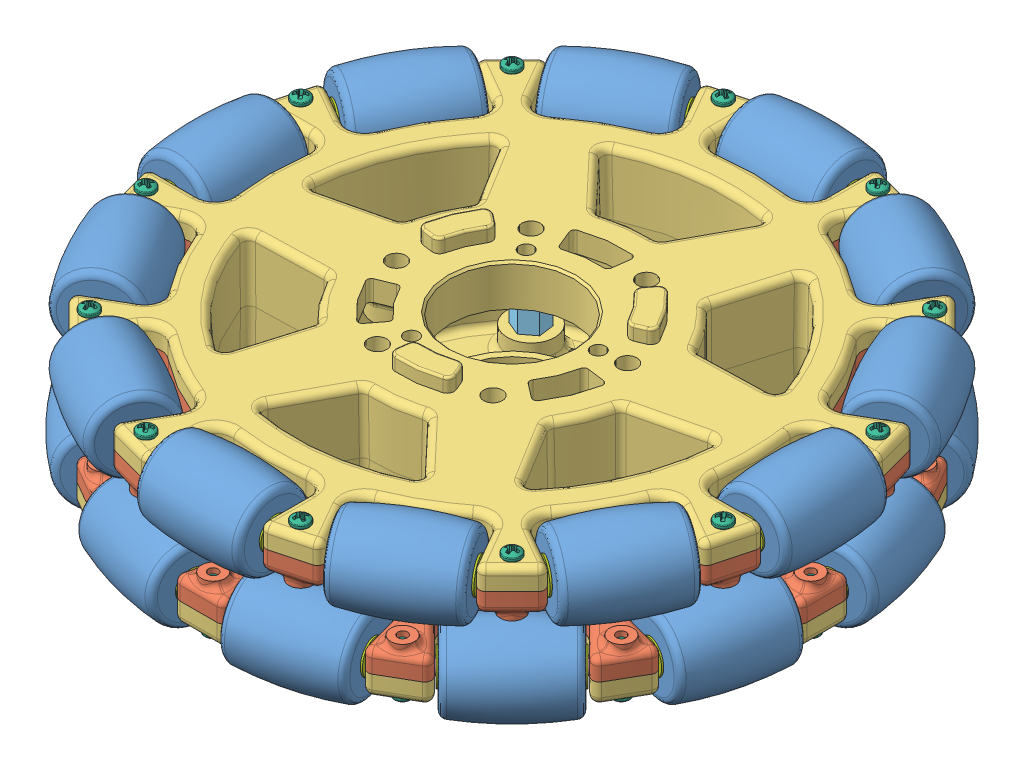
SolidWorks assembly 217-2585.20121203, configuration Default. Lengths in mm.
Overall size (174.23 42.44 174.23).
129 component instances, 7 part files, 0 mates.
Components (placement in the parent):
- 217-2585-001 Rev1-1: 217-2585-001 Rev1 [Default] at (0 9.4629 -66.8297) x (1 0 0) z (0 -0.857126 0.515108) size (24.13 18.81 18.81)
- 217-2585-002 Rev1-1: 217-2585-002 Rev1 [Default] x (1 0 0) z (0 1 0) size (145.16 145.16 19.05)
- 217-2585-001 Rev1-2: 217-2585-001 Rev1 [Default] at (47.2557 -9.4629 47.2557) x (-0.707107 0 0.707107) z (-0.700403 -0.137373 -0.700403) size (24.13 18.81 18.81)
- 217-2585-001 Rev1-3: 217-2585-001 Rev1 [Default] at (17.2968 -9.4629 64.5525) x (-0.965926 0 0.258819) z (-0.256365 -0.137373 -0.956768) size (24.13 18.81 18.81)
- 217-2585-001 Rev1-4: 217-2585-001 Rev1 [Default] at (-17.2968 -9.4629 64.5525) x (-0.965926 0 -0.258819) z (0.256365 -0.137373 -0.956768) size (24.13 18.81 18.81)
- 217-2585-001 Rev1-5: 217-2585-001 Rev1 [Default] at (-47.2557 -9.4629 47.2557) x (-0.707107 0 -0.707107) z (0.700403 -0.137373 -0.700403) size (24.13 18.81 18.81)
- 217-2585-001 Rev1-6: 217-2585-001 Rev1 [Default] at (-64.5525 -9.4629 17.2968) x (-0.258819 0 -0.965926) z (0.956768 -0.137373 -0.256365) size (24.13 18.81 18.81)
- 217-2585-001 Rev1-7: 217-2585-001 Rev1 [Default] at (-64.5525 -9.4629 -17.2968) x (0.258819 0 -0.965926) z (0.956768 -0.137373 0.256365) size (24.13 18.81 18.81)
- 217-2585-001 Rev1-8: 217-2585-001 Rev1 [Default] at (-47.2557 -9.4629 -47.2557) x (0.707107 0 -0.707107) z (0.700403 -0.137373 0.700403) size (24.13 18.81 18.81)
- 217-2585-001 Rev1-9: 217-2585-001 Rev1 [Default] at (-17.2968 -9.4629 -64.5525) x (0.965926 0 -0.258819) z (0.256365 -0.137373 0.956768) size (24.13 18.81 18.81)
- 217-2585-001 Rev1-10: 217-2585-001 Rev1 [Default] at (17.2968 -9.4629 -64.5525) x (0.965926 0 0.258819) z (-0.256365 -0.137373 0.956768) size (24.13 18.81 18.81)
- 217-2585-001 Rev1-11: 217-2585-001 Rev1 [Default] at (47.2557 -9.4629 -47.2557) x (0.707107 0 0.707107) z (-0.700403 -0.137373 0.700403) size (24.13 18.81 18.81)
- 217-2585-001 Rev1-12: 217-2585-001 Rev1 [Default] at (64.5525 -9.4629 -17.2968) x (0.258819 0 0.965926) z (-0.956768 -0.137373 0.256365) size (24.13 18.81 18.81)
- 217-2585-001 Rev1-13: 217-2585-001 Rev1 [Default] at (64.5525 -9.4629 17.2968) x (-0.258819 0 0.965926) z (-0.956768 -0.137373 -0.256365) size (24.13 18.81 18.81)
- 217-2585-003 Rev2-1: 217-2585-003 Rev2 [Default] at (0 -9.525 0) x (0.965926 0 -0.258819) z (0 -1 0) size (142.26 142.26 17.6)
- 217-2585-004 Rev1-1: 217-2585-004 Rev1 [Default] at (-57.9397 9.4629 -33.3049) x (0.5 0 -0.866025) z (-0.558431 0.764334 -0.32241) size (30.16 3 3)
- 217-2585-004 Rev1-2: 217-2585-004 Rev1 [Default] at (-64.5197 -9.4629 -17.4195) x (0.258819 0 -0.965926) z (-0.83871 -0.496046 -0.224732) size (30.16 3 3)
- 217-2585-003 Rev2-2: 217-2585-003 Rev2 [Default] at (0 9.525 0) x (-1 0 0) z (0 1 0) size (142.26 142.26 17.6)
- 217-2585-004 Rev1-3: 217-2585-004 Rev1 [Default] at (-33.5248 9.4629 -57.8127) x (0.866025 0 -0.5) z (-0.32241 0.764334 -0.558431) size (30.16 3 3)
- 217-2585-004 Rev1-4: 217-2585-004 Rev1 [Default] at (-0.127 9.4629 -66.8297) x (1 0 0) z (0 0.764334 -0.644821) size (30.16 3 3)
- 217-2585-004 Rev1-5: 217-2585-004 Rev1 [Default] at (33.3049 9.4629 -57.9397) x (0.866025 0 0.5) z (0.32241 0.764334 -0.558431) size (30.16 3 3)
- 217-2585-004 Rev1-6: 217-2585-004 Rev1 [Default] at (57.8127 9.4629 -33.5248) x (0.5 0 0.866025) z (0.558431 0.764334 -0.32241) size (30.16 3 3)
- 217-2585-004 Rev1-7: 217-2585-004 Rev1 [Default] at (66.8297 9.4629 -0.127) x (0 0 1) z (0.644821 0.764334 0) size (30.16 3 3)
- 217-2585-004 Rev1-8: 217-2585-004 Rev1 [Default] at (57.9397 9.4629 33.3049) x (-0.5 0 0.866025) z (0.558431 0.764334 0.32241) size (30.16 3 3)
- 217-2585-004 Rev1-9: 217-2585-004 Rev1 [Default] at (33.5248 9.4629 57.8127) x (-0.866025 0 0.5) z (0.32241 0.764334 0.558431) size (30.16 3 3)
- 217-2585-004 Rev1-10: 217-2585-004 Rev1 [Default] at (0.127 9.4629 66.8297) x (-1 0 0) z (0 0.764334 0.644821) size (30.16 3 3)
- 217-2585-004 Rev1-11: 217-2585-004 Rev1 [Default] at (-33.3049 9.4629 57.9397) x (-0.866025 0 -0.5) z (-0.32241 0.764334 0.558431) size (30.16 3 3)
- 217-2585-004 Rev1-12: 217-2585-004 Rev1 [Default] at (-57.8127 9.4629 33.5248) x (-0.5 0 -0.866025) z (-0.558431 0.764334 0.32241) size (30.16 3 3)
- 217-2585-004 Rev1-13: 217-2585-004 Rev1 [Default] at (-66.8297 9.4629 0.127) x (0 0 -1) z (-0.644821 0.764334 0) size (30.16 3 3)
- 217-2585-004 Rev1-14: 217-2585-004 Rev1 [Default] at (-47.1659 -9.4629 -47.3455) x (0.707107 0 -0.707107) z (-0.613978 -0.496046 -0.613978) size (30.16 3 3)
- 217-2585-004 Rev1-15: 217-2585-004 Rev1 [Default] at (-17.1741 -9.4629 -64.5854) x (0.965926 0 -0.258819) z (-0.224732 -0.496046 -0.83871) size (30.16 3 3)
- 217-2585-004 Rev1-16: 217-2585-004 Rev1 [Default] at (17.4195 -9.4629 -64.5197) x (0.965926 0 0.258819) z (0.224732 -0.496046 -0.83871) size (30.16 3 3)
- 217-2585-004 Rev1-17: 217-2585-004 Rev1 [Default] at (47.3455 -9.4629 -47.1659) x (0.707107 0 0.707107) z (0.613978 -0.496046 -0.613978) size (30.16 3 3)
- 217-2585-004 Rev1-18: 217-2585-004 Rev1 [Default] at (64.5854 -9.4629 -17.1741) x (0.258819 0 0.965926) z (0.83871 -0.496046 -0.224732) size (30.16 3 3)
- 217-2585-004 Rev1-19: 217-2585-004 Rev1 [Default] at (64.5197 -9.4629 17.4195) x (-0.258819 0 0.965926) z (0.83871 -0.496046 0.224732) size (30.16 3 3)
- 217-2585-004 Rev1-20: 217-2585-004 Rev1 [Default] at (47.1659 -9.4629 47.3455) x (-0.707107 0 0.707107) z (0.613978 -0.496046 0.613978) size (30.16 3 3)
- 217-2585-004 Rev1-21: 217-2585-004 Rev1 [Default] at (17.1741 -9.4629 64.5854) x (-0.965926 0 0.258819) z (0.224732 -0.496046 0.83871) size (30.16 3 3)
- 217-2585-004 Rev1-22: 217-2585-004 Rev1 [Default] at (-17.4195 -9.4629 64.5197) x (-0.965926 0 -0.258819) z (-0.224732 -0.496046 0.83871) size (30.16 3 3)
- 217-2585-004 Rev1-23: 217-2585-004 Rev1 [Default] at (-47.3455 -9.4629 47.1659) x (-0.707107 0 -0.707107) z (-0.613978 -0.496046 0.613978) size (30.16 3 3)
- 217-2585-004 Rev1-24: 217-2585-004 Rev1 [Default] at (-64.5854 -9.4629 17.1741) x (-0.258819 0 -0.965926) z (-0.83871 -0.496046 0.224732) size (30.16 3 3)
- 217-2585-001 Rev1-14: 217-2585-001 Rev1 [Default] at (33.4148 9.4629 -57.8762) x (0.866025 0 0.5) z (-0.257554 -0.857126 0.446096) size (24.13 18.81 18.81)
- 217-2585-001 Rev1-15: 217-2585-001 Rev1 [Default] at (57.8762 9.4629 -33.4148) x (0.5 0 0.866025) z (-0.446096 -0.857126 0.257554) size (24.13 18.81 18.81)
- 217-2585-001 Rev1-16: 217-2585-001 Rev1 [Default] at (66.8297 9.4629 0) x (0 0 1) z (-0.515108 -0.857126 0) size (24.13 18.81 18.81)
- 217-2585-001 Rev1-17: 217-2585-001 Rev1 [Default] at (57.8762 9.4629 33.4148) x (-0.5 0 0.866025) z (-0.446096 -0.857126 -0.257554) size (24.13 18.81 18.81)
- 217-2585-001 Rev1-18: 217-2585-001 Rev1 [Default] at (33.4148 9.4629 57.8762) x (-0.866025 0 0.5) z (-0.257554 -0.857126 -0.446096) size (24.13 18.81 18.81)
- 217-2585-001 Rev1-19: 217-2585-001 Rev1 [Default] at (0 9.4629 66.8297) x (-1 0 0) z (0 -0.857126 -0.515108) size (24.13 18.81 18.81)
- 217-2585-001 Rev1-20: 217-2585-001 Rev1 [Default] at (-33.4148 9.4629 57.8762) x (-0.866025 0 -0.5) z (0.257554 -0.857126 -0.446096) size (24.13 18.81 18.81)
- 217-2585-001 Rev1-21: 217-2585-001 Rev1 [Default] at (-57.8762 9.4629 33.4148) x (-0.5 0 -0.866025) z (0.446096 -0.857126 -0.257554) size (24.13 18.81 18.81)
- 217-2585-001 Rev1-22: 217-2585-001 Rev1 [Default] at (-66.8297 9.4629 0) x (0 0 -1) z (0.515108 -0.857126 0) size (24.13 18.81 18.81)
- 217-2585-001 Rev1-23: 217-2585-001 Rev1 [Default] at (-57.8762 9.4629 -33.4148) x (0.5 0 -0.866025) z (0.446096 -0.857126 0.257554) size (24.13 18.81 18.81)
- 217-2585-001 Rev1-24: 217-2585-001 Rev1 [Default] at (-33.4148 9.4629 -57.8762) x (0.866025 0 -0.5) z (0.257554 -0.857126 0.446096) size (24.13 18.81 18.81)
- BEAM-0750-1: BEAM-0750 [Default] at (-23.6088 0 3.1082) x (0.793353 0 -0.608761) z (0.608761 0 0.793353) size (7.33 19.93 6.35)
- BEAM-0750-2: BEAM-0750 [Default] at (-14.4961 0 -18.8917) x (0.92388 0 0.382683) z (-0.382683 0 0.92388) size (7.33 19.93 6.35)
- BEAM-0750-3: BEAM-0750 [Default] at (9.1126 0 -21.9999) x (0.130526 0 0.991445) z (-0.991445 0 0.130526) size (7.33 19.93 6.35)
- BEAM-0750-4: BEAM-0750 [Default] at (23.6088 0 -3.1082) x (-0.793353 0 0.608761) z (-0.608761 0 -0.793353) size (7.33 19.93 6.35)
- BEAM-0750-5: BEAM-0750 [Default] at (14.4961 0 18.8917) x (-0.92388 0 -0.382683) z (0.382683 0 -0.92388) size (7.33 19.93 6.35)
- BEAM-0750-6: BEAM-0750 [Default] at (-9.1126 0 21.9999) x (-0.130526 0 -0.991445) z (0.991445 0 -0.130526) size (7.33 19.93 6.35)
- 90116A020_90116A020-1: 90116A020_90116A020 [Default] at (34.544 -4.2875 -59.832) x (0.956072 0 -0.293131) z (0 -1 0) size (4 4 11.7)
- 90116A020_90116A020-2: 90116A020_90116A020 [Default] at (59.832 -4.2875 -34.544) x (0.974548 0 0.224177) z (0 -1 0) size (4 4 11.7)
- 90116A020_90116A020-3: 90116A020_90116A020 [Default] at (69.088 -4.2875 0) x (0.731895 0 0.681417) z (0 -1 0) size (4 4 11.7)
- 90116A020_90116A020-4: 90116A020_90116A020 [Default] at (59.832 -4.2875 34.544) x (0.293131 0 0.956072) z (0 -1 0) size (4 4 11.7)
- 90116A020_90116A020-5: 90116A020_90116A020 [Default] at (34.544 -4.2875 59.832) x (-0.224177 0 0.974548) z (0 -1 0) size (4 4 11.7)
- 90116A020_90116A020-6: 90116A020_90116A020 [Default] at (0 -4.2875 69.088) x (-0.681417 0 0.731895) z (0 -1 0) size (4 4 11.7)
- 90116A020_90116A020-7: 90116A020_90116A020 [Default] at (-34.544 -4.2875 59.832) x (-0.956072 0 0.293131) z (0 -1 0) size (4 4 11.7)
- 90116A020_90116A020-8: 90116A020_90116A020 [Default] at (-59.832 -4.2875 34.544) x (-0.974548 0 -0.224177) z (0 -1 0) size (4 4 11.7)
- 90116A020_90116A020-9: 90116A020_90116A020 [Default] at (-69.088 -4.2875 0) x (-0.731895 0 -0.681417) z (0 -1 0) size (4 4 11.7)
- 90116A020_90116A020-10: 90116A020_90116A020 [Default] at (-59.832 -4.2875 -34.544) x (-0.293131 0 -0.956072) z (0 -1 0) size (4 4 11.7)
- 90116A020_90116A020-11: 90116A020_90116A020 [Default] at (-34.544 -4.2875 -59.832) x (0.224177 0 -0.974548) z (0 -1 0) size (4 4 11.7)
- 90116A020_90116A020-12: 90116A020_90116A020 [Default] at (0 -4.2875 -69.088) x (0.681417 0 -0.731895) z (0 -1 0) size (4 4 11.7)
- 90116A020_90116A020-13: 90116A020_90116A020 [Default] at (66.7339 4.2875 -17.8813) x (-0.938474 0 -0.34535) z (0 1 0) size (4 4 11.7)
- 90116A020_90116A020-14: 90116A020_90116A020 [Default] at (66.7339 4.2875 17.8813) x (-0.640068 0 -0.768319) z (0 1 0) size (4 4 11.7)
- 90116A020_90116A020-15: 90116A020_90116A020 [Default] at (48.8526 4.2875 48.8526) x (-0.170155 0 -0.985417) z (0 1 0) size (4 4 11.7)
- 90116A020_90116A020-16: 90116A020_90116A020 [Default] at (17.8813 4.2875 66.7339) x (0.34535 0 -0.938474) z (0 1 0) size (4 4 11.7)
- 90116A020_90116A020-17: 90116A020_90116A020 [Default] at (-17.8813 4.2875 66.7339) x (0.768319 0 -0.640068) z (0 1 0) size (4 4 11.7)
- 90116A020_90116A020-18: 90116A020_90116A020 [Default] at (-48.8526 4.2875 48.8526) x (0.985417 0 -0.170155) z (0 1 0) size (4 4 11.7)
- 90116A020_90116A020-19: 90116A020_90116A020 [Default] at (-66.7339 4.2875 17.8813) x (0.938474 0 0.34535) z (0 1 0) size (4 4 11.7)
- 90116A020_90116A020-20: 90116A020_90116A020 [Default] at (-66.7339 4.2875 -17.8813) x (0.640068 0 0.768319) z (0 1 0) size (4 4 11.7)
- 90116A020_90116A020-21: 90116A020_90116A020 [Default] at (-48.8526 4.2875 -48.8526) x (0.170155 0 0.985417) z (0 1 0) size (4 4 11.7)
- 90116A020_90116A020-22: 90116A020_90116A020 [Default] at (-17.8813 4.2875 -66.7339) x (-0.34535 0 0.938474) z (0 1 0) size (4 4 11.7)
- 90116A020_90116A020-23: 90116A020_90116A020 [Default] at (17.8813 4.2875 -66.7339) x (-0.768319 0 0.640068) z (0 1 0) size (4 4 11.7)
- 90116A020_90116A020-24: 90116A020_90116A020 [Default] at (48.8526 4.2875 -48.8526) x (-0.985417 0 0.170155) z (0 1 0) size (4 4 11.7)
- 217-2584-005 Rev1 A-1: 217-2584-005 Rev1 A [Default] at (-7.3025 9.4629 -66.8297) x (0 -0.523633 0.851944) z (-1 0 0) size (7.38 7.38 9.92)
- 217-2584-005 Rev1 A-2: 217-2584-005 Rev1 A [Default] at (7.3025 9.4629 -66.8297) x (0 -0.987336 0.15864) z (1 0 0) size (7.38 7.38 9.92)
- 217-2584-005 Rev1 A-3: 217-2584-005 Rev1 A [Default] at (-24.3505 -9.4629 -62.6625) x (-0.242217 -0.352388 -0.903966) z (-0.965926 0 0.258819) size (7.38 7.38 9.92)
- 217-2584-005 Rev1 A-4: 217-2584-005 Rev1 A [Default] at (-10.2431 -9.4629 -66.4425) x (0.244105 0.332373 0.911011) z (0.965926 0 -0.258819) size (7.38 7.38 9.92)
- 217-2584-005 Rev1 A-5: 217-2584-005 Rev1 A [Default] at (10.2431 -9.4629 -66.4425) x (0.242217 -0.352388 -0.903966) z (-0.965926 0 -0.258819) size (7.38 7.38 9.92)
- 217-2584-005 Rev1 A-6: 217-2584-005 Rev1 A [Default] at (42.0921 -9.4629 -52.4194) x (0.661749 -0.352388 -0.661749) z (-0.707107 0 -0.707107) size (7.38 7.38 9.92)
- 217-2584-005 Rev1 A-7: 217-2584-005 Rev1 A [Default] at (62.6625 -9.4629 -24.3505) x (0.903966 -0.352388 -0.242217) z (-0.258819 0 -0.965926) size (7.38 7.38 9.92)
- 217-2584-005 Rev1 A-8: 217-2584-005 Rev1 A [Default] at (66.4425 -9.4629 10.2431) x (0.903966 -0.352388 0.242217) z (0.258819 0 -0.965926) size (7.38 7.38 9.92)
- 217-2584-005 Rev1 A-9: 217-2584-005 Rev1 A [Default] at (52.4194 -9.4629 42.0921) x (0.661749 -0.352388 0.661749) z (0.707107 0 -0.707107) size (7.38 7.38 9.92)
- 217-2584-005 Rev1 A-10: 217-2584-005 Rev1 A [Default] at (24.3505 -9.4629 62.6625) x (0.242217 -0.352388 0.903966) z (0.965926 0 -0.258819) size (7.38 7.38 9.92)
- 217-2584-005 Rev1 A-11: 217-2584-005 Rev1 A [Default] at (-10.2431 -9.4629 66.4425) x (-0.242217 -0.352388 0.903966) z (0.965926 0 0.258819) size (7.38 7.38 9.92)
- 217-2584-005 Rev1 A-12: 217-2584-005 Rev1 A [Default] at (-42.0921 -9.4629 52.4194) x (-0.661749 -0.352388 0.661749) z (0.707107 0 0.707107) size (7.38 7.38 9.92)
- 217-2584-005 Rev1 A-13: 217-2584-005 Rev1 A [Default] at (-62.6625 -9.4629 24.3505) x (-0.903966 -0.352388 0.242217) z (0.258819 0 0.965926) size (7.38 7.38 9.92)
- 217-2584-005 Rev1 A-14: 217-2584-005 Rev1 A [Default] at (-66.4425 -9.4629 -10.2431) x (-0.903966 -0.352388 -0.242217) z (-0.258819 0 0.965926) size (7.38 7.38 9.92)
- 217-2584-005 Rev1 A-15: 217-2584-005 Rev1 A [Default] at (-52.4194 -9.4629 -42.0921) x (-0.661749 -0.352388 -0.661749) z (-0.707107 0 0.707107) size (7.38 7.38 9.92)
- 217-2584-005 Rev1 A-16: 217-2584-005 Rev1 A [Default] at (24.3505 -9.4629 -62.6625) x (-0.244105 0.332373 0.911011) z (0.965926 0 0.258819) size (7.38 7.38 9.92)
- 217-2584-005 Rev1 A-17: 217-2584-005 Rev1 A [Default] at (52.4194 -9.4629 -42.0921) x (-0.666906 0.332373 0.666906) z (0.707107 0 0.707107) size (7.38 7.38 9.92)
- 217-2584-005 Rev1 A-18: 217-2584-005 Rev1 A [Default] at (66.4425 -9.4629 -10.2431) x (-0.911011 0.332373 0.244105) z (0.258819 0 0.965926) size (7.38 7.38 9.92)
- 217-2584-005 Rev1 A-19: 217-2584-005 Rev1 A [Default] at (62.6625 -9.4629 24.3505) x (-0.911011 0.332373 -0.244105) z (-0.258819 0 0.965926) size (7.38 7.38 9.92)
- 217-2584-005 Rev1 A-20: 217-2584-005 Rev1 A [Default] at (42.0921 -9.4629 52.4194) x (-0.666906 0.332373 -0.666906) z (-0.707107 0 0.707107) size (7.38 7.38 9.92)
- 217-2584-005 Rev1 A-21: 217-2584-005 Rev1 A [Default] at (10.2431 -9.4629 66.4425) x (-0.244105 0.332373 -0.911011) z (-0.965926 0 0.258819) size (7.38 7.38 9.92)
- 217-2584-005 Rev1 A-22: 217-2584-005 Rev1 A [Default] at (-24.3505 -9.4629 62.6625) x (0.244105 0.332373 -0.911011) z (-0.965926 0 -0.258819) size (7.38 7.38 9.92)
- 217-2584-005 Rev1 A-23: 217-2584-005 Rev1 A [Default] at (-52.4194 -9.4629 42.0921) x (0.666906 0.332373 -0.666906) z (-0.707107 0 -0.707107) size (7.38 7.38 9.92)
- 217-2584-005 Rev1 A-24: 217-2584-005 Rev1 A [Default] at (-66.4425 -9.4629 10.2431) x (0.911011 0.332373 -0.244105) z (-0.258819 0 -0.965926) size (7.38 7.38 9.92)
- 217-2584-005 Rev1 A-25: 217-2584-005 Rev1 A [Default] at (-62.6625 -9.4629 -24.3505) x (0.911011 0.332373 0.244105) z (0.258819 0 -0.965926) size (7.38 7.38 9.92)
- 217-2584-005 Rev1 A-26: 217-2584-005 Rev1 A [Default] at (-42.0921 -9.4629 -52.4194) x (0.666906 0.332373 0.666906) z (0.707107 0 -0.707107) size (7.38 7.38 9.92)
- 217-2584-005 Rev1 A-27: 217-2584-005 Rev1 A [Default] at (39.739 9.4629 -54.225) x (-0.07932 -0.987336 0.137386) z (0.866025 0 0.5) size (7.38 7.38 9.92)
- 217-2584-005 Rev1 A-28: 217-2584-005 Rev1 A [Default] at (61.5275 9.4629 -27.0907) x (-0.137386 -0.987336 0.07932) z (0.5 0 0.866025) size (7.38 7.38 9.92)
- 217-2584-005 Rev1 A-29: 217-2584-005 Rev1 A [Default] at (66.8297 9.4629 7.3025) x (-0.15864 -0.987336 0) z (0 0 1) size (7.38 7.38 9.92)
- 217-2584-005 Rev1 A-30: 217-2584-005 Rev1 A [Default] at (54.225 9.4629 39.739) x (-0.137386 -0.987336 -0.07932) z (-0.5 0 0.866025) size (7.38 7.38 9.92)
- 217-2584-005 Rev1 A-31: 217-2584-005 Rev1 A [Default] at (27.0907 9.4629 61.5275) x (-0.07932 -0.987336 -0.137386) z (-0.866025 0 0.5) size (7.38 7.38 9.92)
- 217-2584-005 Rev1 A-32: 217-2584-005 Rev1 A [Default] at (-7.3025 9.4629 66.8297) x (0 -0.987336 -0.15864) z (-1 0 0) size (7.38 7.38 9.92)
- 217-2584-005 Rev1 A-33: 217-2584-005 Rev1 A [Default] at (-39.739 9.4629 54.225) x (0.07932 -0.987336 -0.137386) z (-0.866025 0 -0.5) size (7.38 7.38 9.92)
- 217-2584-005 Rev1 A-34: 217-2584-005 Rev1 A [Default] at (-61.5275 9.4629 27.0907) x (0.137386 -0.987336 -0.07932) z (-0.5 0 -0.866025) size (7.38 7.38 9.92)
- 217-2584-005 Rev1 A-35: 217-2584-005 Rev1 A [Default] at (-66.8297 9.4629 -7.3025) x (0.15864 -0.987336 0) z (0 0 -1) size (7.38 7.38 9.92)
- 217-2584-005 Rev1 A-36: 217-2584-005 Rev1 A [Default] at (-54.225 9.4629 -39.739) x (0.137386 -0.987336 0.07932) z (0.5 0 -0.866025) size (7.38 7.38 9.92)
- 217-2584-005 Rev1 A-37: 217-2584-005 Rev1 A [Default] at (-27.0907 9.4629 -61.5275) x (0.07932 -0.987336 0.137386) z (0.866025 0 -0.5) size (7.38 7.38 9.92)
- 217-2584-005 Rev1 A-38: 217-2584-005 Rev1 A [Default] at (27.0907 9.4629 -61.5275) x (-0.425972 -0.523633 0.737805) z (-0.866025 0 -0.5) size (7.38 7.38 9.92)
- 217-2584-005 Rev1 A-39: 217-2584-005 Rev1 A [Default] at (54.225 9.4629 -39.739) x (-0.737805 -0.523633 0.425972) z (-0.5 0 -0.866025) size (7.38 7.38 9.92)
- 217-2584-005 Rev1 A-40: 217-2584-005 Rev1 A [Default] at (66.8297 9.4629 -7.3025) x (-0.851944 -0.523633 0) z (0 0 -1) size (7.38 7.38 9.92)
- 217-2584-005 Rev1 A-41: 217-2584-005 Rev1 A [Default] at (61.5275 9.4629 27.0907) x (-0.737805 -0.523633 -0.425972) z (0.5 0 -0.866025) size (7.38 7.38 9.92)
- 217-2584-005 Rev1 A-42: 217-2584-005 Rev1 A [Default] at (39.739 9.4629 54.225) x (-0.425972 -0.523633 -0.737805) z (0.866025 0 -0.5) size (7.38 7.38 9.92)
- 217-2584-005 Rev1 A-43: 217-2584-005 Rev1 A [Default] at (7.3025 9.4629 66.8297) x (0 -0.523633 -0.851944) z (1 0 0) size (7.38 7.38 9.92)
- 217-2584-005 Rev1 A-44: 217-2584-005 Rev1 A [Default] at (-27.0907 9.4629 61.5275) x (0.425972 -0.523633 -0.737805) z (0.866025 0 0.5) size (7.38 7.38 9.92)
- 217-2584-005 Rev1 A-45: 217-2584-005 Rev1 A [Default] at (-54.225 9.4629 39.739) x (0.737805 -0.523633 -0.425972) z (0.5 0 0.866025) size (7.38 7.38 9.92)
- 217-2584-005 Rev1 A-46: 217-2584-005 Rev1 A [Default] at (-66.8297 9.4629 7.3025) x (0.851944 -0.523633 0) z (0 0 1) size (7.38 7.38 9.92)
- 217-2584-005 Rev1 A-47: 217-2584-005 Rev1 A [Default] at (-61.5275 9.4629 -27.0907) x (0.737805 -0.523633 0.425972) z (-0.5 0 0.866025) size (7.38 7.38 9.92)
- 217-2584-005 Rev1 A-48: 217-2584-005 Rev1 A [Default] at (-39.739 9.4629 -54.225) x (0.425972 -0.523633 0.737805) z (-0.866025 0 0.5) size (7.38 7.38 9.92)
